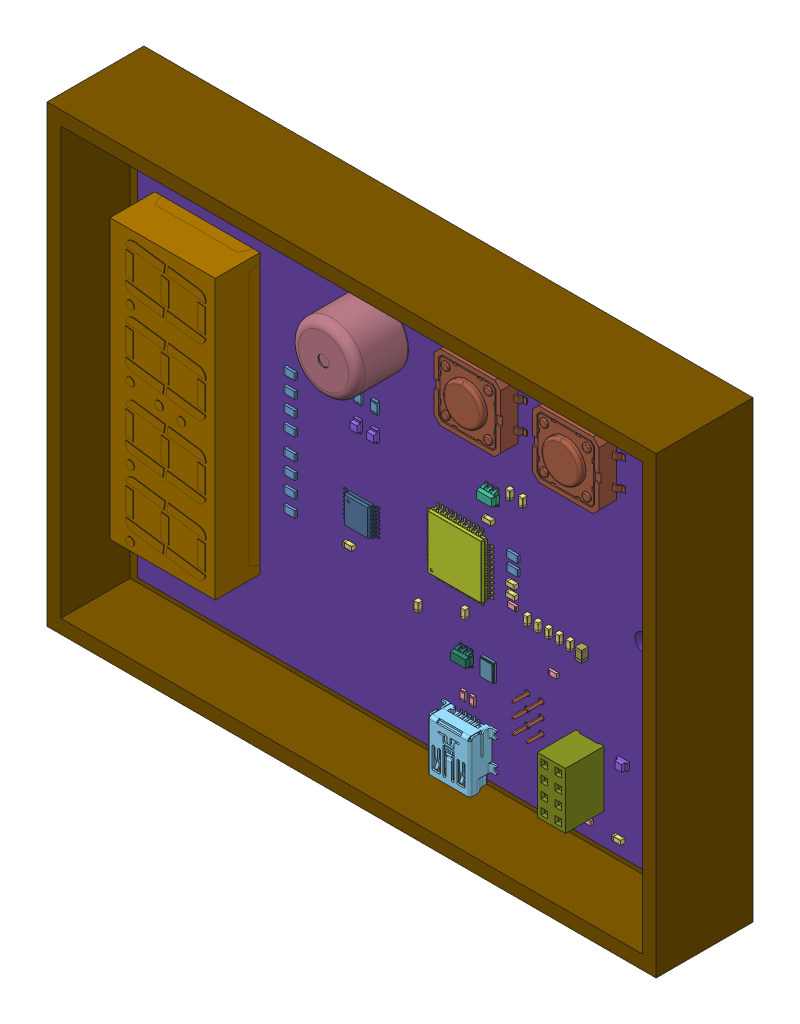
SolidWorks assembly Phase_B_Encloser_ASM_One, configuration Default. Lengths in mm.
Overall size (110 82 17.5).
96 component instances, 18 part files, 1 mates.
Components (placement in the parent):
- R_0805_2012Metric.STEP-1: R_0805_2012Metric.STEP [Default] at (136.75 -75.9525 1.63) x (0 1 0) z (0 0 1) size (2 1.2 0.45)
  - SOLID.STEP-1: SOLID.STEP [Default] at origin size (2 1.2 0.45)
- PinSocket_2x03_P2.54mm_Vertical.STEP-1: PinSocket_2x03_P2.54mm_Vertical.STEP [Default] at (166.9225 -107.335 1.13) x (-1 0 0) z (0 0 -1) size (5.08 7.62 10.1)
  - SOLID-0.STEP-1: SOLID-0.STEP [Default] at origin size (5.08 7.62 10.1)
- C_0603_1608Metric.STEP-1: C_0603_1608Metric.STEP [Default] at (175.1083 -95.3579 1.63) x (0 1 0) z (0 0 1) size (1.6 0.8 0.8)
  - SOLID-1.STEP-1: SOLID-1.STEP [Default] at origin size (1.6 0.8 0.8)
- C_0603_1608Metric.STEP-2: C_0603_1608Metric.STEP [Default] at (167.3681 -95.3139 1.63) x (0 1 0) z (0 0 1) size (1.6 0.8 0.8)
  - SOLID-1.STEP-1: SOLID-1.STEP [Default] at origin size (1.6 0.8 0.8)
- R_0603_1608Metric.STEP-1: R_0603_1608Metric.STEP [Default] at (178.1154 -121.5005 1.63) size (1.6 0.8 0.45)
  - SOLID-2.STEP-1: SOLID-2.STEP [Default] at origin size (1.6 0.8 0.45)
- R_0805_2012Metric.STEP-2: R_0805_2012Metric.STEP [Default] at (164.6638 -86.8628 1.63) size (2 1.2 0.45)
  - SOLID.STEP-1: SOLID.STEP [Default] at origin size (2 1.2 0.45)
- USB_Mini-B_Lumberg_2486_01_Horizontal.STEP-1: USB_Mini-B_Lumberg_2486_01_Horizontal.STEP [Default] at (156.7225 -119.07 1.63) size (9.9 9.21 5)
  - SOLID-3.STEP-1: SOLID-3.STEP [Default] at origin size (9.9 9.21 5)
- SOT-23-5.STEP-1: SOT-23-5.STEP [Default] at (160.6831 -79.2295 1.63) x (0 -1 0) z (0 0 1) size (2.8 2.9 1.55)
  - SOLID-4.STEP-1: SOLID-4.STEP [Default] at origin size (2.8 2.9 1.55)
- R_0805_2012Metric.STEP-3: R_0805_2012Metric.STEP [Default] at (124.46 -81.28 1.63) size (2 1.2 0.45)
  - SOLID.STEP-1: SOLID.STEP [Default] at origin size (2 1.2 0.45)
- TQFP-44_10x10mm_P0.8mm.STEP-1: TQFP-44_10x10mm_P0.8mm.STEP [Default] at (154.94 -91.44 1.63) x (0 1 0) z (0 0 1) size (12 12 1.1)
  - SOLID-5.STEP-1: SOLID-5.STEP [Default] at origin size (12 12 1.1)
- LED_0805_2012Metric.STEP-1: LED_0805_2012Metric.STEP [Default] at (136.66 -80.3425 1.63) x (0 1 0) z (0 0 1) size (2 1.25 1.1)
  - SOLID-6.STEP-1: SOLID-6.STEP [Default] at origin size (2 1.25 1.1)
- C_0603_1608Metric.STEP-3: C_0603_1608Metric.STEP [Default] at (164.6143 -92.9198 1.63) size (1.6 0.8 0.8)
  - SOLID-1.STEP-1: SOLID-1.STEP [Default] at origin size (1.6 0.8 0.8)
- CA56-12EWA.STEP-1: CA56-12EWA.STEP [Default] at (101.6 -81.28 1.63) size (19 50.3 12.2)
  - SOLID-7.STEP-1: SOLID-7.STEP [Default] at origin size (19 50.3 12.2)
- C_0603_1608Metric.STEP-4: C_0603_1608Metric.STEP [Default] at (160.3412 -83.2998 1.63) x (-1 0 0) z (0 0 1) size (1.6 0.8 0.8)
  - SOLID-1.STEP-1: SOLID-1.STEP [Default] at origin size (1.6 0.8 0.8)
- TSSOP-16_4.4x5mm_P0.65mm.STEP-1: TSSOP-16_4.4x5mm_P0.65mm.STEP [Default] at (137.16 -93.98 1.63) size (6.4 5 1.1)
  - SOLID-8.STEP-1: SOLID-8.STEP [Default] at origin size (6.4 5 1.1)
- PTS125_SMD_Button.STEP-1: PTS125_SMD_Button.STEP [Default] at (177.0425 -64.155 1.63) x (0 1 0) z (1 0 0) size (12 4.3 15.3)
  - SOLID-9.STEP-1: SOLID-9.STEP [Default] at origin size (12 4.3 15.3)
- C_0603_1608Metric.STEP-5: C_0603_1608Metric.STEP [Default] at (171.2411 -95.3579 1.63) x (0 1 0) z (0 0 1) size (1.6 0.8 0.8)
  - SOLID-1.STEP-1: SOLID-1.STEP [Default] at origin size (1.6 0.8 0.8)
- R_0603_1608Metric.STEP-2: R_0603_1608Metric.STEP [Default] at (171.895 -101.6 1.63) size (1.6 0.8 0.45)
  - SOLID-2.STEP-1: SOLID-2.STEP [Default] at origin size (1.6 0.8 0.45)
- C_0603_1608Metric.STEP-6: C_0603_1608Metric.STEP [Default] at (135.1928 -99.8408 1.63) x (-1 0 0) z (0 0 1) size (1.6 0.8 0.8)
  - SOLID-1.STEP-1: SOLID-1.STEP [Default] at origin size (1.6 0.8 0.8)
- C_0805_2012Metric.STEP-1: C_0805_2012Metric.STEP [Default] at (177.4051 -95.4592 1.63) x (0 1 0) z (0 0 1) size (2 1.25 1.25)
  - SOLID-10.STEP-1: SOLID-10.STEP [Default] at origin size (2 1.25 1.25)
- R_0805_2012Metric.STEP-4: R_0805_2012Metric.STEP [Default] at (124.46 -96.93 1.63) size (2 1.2 0.45)
  - SOLID.STEP-1: SOLID.STEP [Default] at origin size (2 1.2 0.45)
- R_0805_2012Metric.STEP-5: R_0805_2012Metric.STEP [Default] at (124.46 -99.88 1.63) size (2 1.2 0.45)
  - SOLID.STEP-1: SOLID.STEP [Default] at origin size (2 1.2 0.45)
- Buzzer_12x9.5RM7.6.STEP-1: Buzzer_12x9.5RM7.6.STEP [Default] at (139.7 -67.955 1.63) x (0 1 0) z (0 0 1) size (12 12 12.53)
  - SOLID-11.STEP-1: SOLID-11.STEP [Default] at origin size (12 12 12.53)
- R_0603_1608Metric.STEP-3: R_0603_1608Metric.STEP [Default] at (164.621 -94.7272 1.63) x (-1 0 0) z (0 0 1) size (1.6 0.8 0.45)
  - SOLID-2.STEP-1: SOLID-2.STEP [Default] at origin size (1.6 0.8 0.45)
- LED_0805_2012Metric.STEP-2: LED_0805_2012Metric.STEP [Default] at (139.7 -80.3425 1.63) x (0 1 0) z (0 0 1) size (2 1.25 1.1)
  - SOLID-6.STEP-1: SOLID-6.STEP [Default] at origin size (2 1.25 1.1)
- R_0603_1608Metric.STEP-4: R_0603_1608Metric.STEP [Default] at (157.3461 -113.1038 1.63) x (0 1 0) z (0 0 1) size (1.6 0.8 0.45)
  - SOLID-2.STEP-1: SOLID-2.STEP [Default] at origin size (1.6 0.8 0.45)
- R_0805_2012Metric.STEP-6: R_0805_2012Metric.STEP [Default] at (164.6674 -88.9903 1.63) size (2 1.2 0.45)
  - SOLID.STEP-1: SOLID.STEP [Default] at origin size (2 1.2 0.45)
- C_0603_1608Metric.STEP-7: C_0603_1608Metric.STEP [Default] at (173.1422 -95.3579 1.63) x (0 1 0) z (0 0 1) size (1.6 0.8 0.8)
  - SOLID-1.STEP-1: SOLID-1.STEP [Default] at origin size (1.6 0.8 0.8)
- C_0603_1608Metric.STEP-8: C_0603_1608Metric.STEP [Default] at (183.7777 -121.5005 1.63) size (1.6 0.8 0.8)
  - SOLID-1.STEP-1: SOLID-1.STEP [Default] at origin size (1.6 0.8 0.8)
- Crystal_SMD_Abracon_ABM8G-4Pin_3.2x2.5mm.STEP-1: Crystal_SMD_Abracon_ABM8G-4Pin_3.2x2.5mm.STEP [Default] at (160.167 -106.8176 1.63) x (0 1 0) z (0 0 1) size (3.2 2.5 0.64)
  - SOLID-12.STEP-1: SOLID-12.STEP [Default] at origin size (3.2 2.5 0.64)
- R_0805_2012Metric.STEP-7: R_0805_2012Metric.STEP [Default] at (124.46 -78.33 1.63) size (2 1.2 0.45)
  - SOLID.STEP-1: SOLID.STEP [Default] at origin size (2 1.2 0.45)
- R_0805_2012Metric.STEP-8: R_0805_2012Metric.STEP [Default] at (139.7 -75.9525 1.63) x (0 1 0) z (0 0 1) size (2 1.2 0.45)
  - SOLID.STEP-1: SOLID.STEP [Default] at origin size (2 1.2 0.45)
- R_0805_2012Metric.STEP-9: R_0805_2012Metric.STEP [Default] at (124.46 -93.98 1.63) size (2 1.2 0.45)
  - SOLID.STEP-1: SOLID.STEP [Default] at origin size (2 1.2 0.45)
- C_0603_1608Metric.STEP-9: C_0603_1608Metric.STEP [Default] at (164.6119 -91.194 1.63) x (-1 0 0) z (0 0 1) size (1.6 0.8 0.8)
  - SOLID-1.STEP-1: SOLID-1.STEP [Default] at origin size (1.6 0.8 0.8)
- C_0603_1608Metric.STEP-10: C_0603_1608Metric.STEP [Default] at (147.6552 -103.0061 1.63) x (0 -1 0) z (0 0 1) size (1.6 0.8 0.8)
  - SOLID-1.STEP-1: SOLID-1.STEP [Default] at origin size (1.6 0.8 0.8)
- C_0603_1608Metric.STEP-11: C_0603_1608Metric.STEP [Default] at (164.2172 -77.2255 1.63) x (0 -1 0) z (0 0 1) size (1.6 0.8 0.8)
  - SOLID-1.STEP-1: SOLID-1.STEP [Default] at origin size (1.6 0.8 0.8)
- C_0603_1608Metric.STEP-12: C_0603_1608Metric.STEP [Default] at (169.3071 -95.3345 1.63) x (0 1 0) z (0 0 1) size (1.6 0.8 0.8)
  - SOLID-1.STEP-1: SOLID-1.STEP [Default] at origin size (1.6 0.8 0.8)
- C_0603_1608Metric.STEP-13: C_0603_1608Metric.STEP [Default] at (156.1028 -99.9047 1.63) x (0 1 0) z (0 0 1) size (1.6 0.8 0.8)
  - SOLID-1.STEP-1: SOLID-1.STEP [Default] at origin size (1.6 0.8 0.8)
- SOT-23-6.STEP-1: SOT-23-6.STEP [Default] at (156.0168 -106.7769 1.63) x (0 1 0) z (0 0 1) size (2.8 2.9 1.55)
  - SOLID-13.STEP-1: SOLID-13.STEP [Default] at origin size (2.8 2.9 1.55)
- R_0805_2012Metric.STEP-10: R_0805_2012Metric.STEP [Default] at (124.46 -91.03 1.63) size (2 1.2 0.45)
  - SOLID.STEP-1: SOLID.STEP [Default] at origin size (2 1.2 0.45)
- R_0805_2012Metric.STEP-11: R_0805_2012Metric.STEP [Default] at (124.46 -84.23 1.63) size (2 1.2 0.45)
  - SOLID.STEP-1: SOLID.STEP [Default] at origin size (2 1.2 0.45)
- C_0603_1608Metric.STEP-14: C_0603_1608Metric.STEP [Default] at (166.5378 -77.2117 1.63) x (0 -1 0) z (0 0 1) size (1.6 0.8 0.8)
  - SOLID-1.STEP-1: SOLID-1.STEP [Default] at origin size (1.6 0.8 0.8)
- R_0805_2012Metric.STEP-12: R_0805_2012Metric.STEP [Default] at (124.46 -87.18 1.63) size (2 1.2 0.45)
  - SOLID.STEP-1: SOLID.STEP [Default] at origin size (2 1.2 0.45)
- PinSocket_2x04_P2.54mm_Vertical.STEP-1: PinSocket_2x04_P2.54mm_Vertical.STEP [Default] at (179.5825 -109.875 1.63) size (5.08 10.16 10.1)
  - SOLID-14.STEP-1: SOLID-14.STEP [Default] at origin size (5.08 10.16 10.1)
- LED_0805_2012Metric.STEP-3: LED_0805_2012Metric.STEP [Default] at (184.4796 -109.4399 1.63) size (2 1.25 1.1)
  - SOLID-6.STEP-1: SOLID-6.STEP [Default] at origin size (2 1.25 1.1)
- R_0603_1608Metric.STEP-5: R_0603_1608Metric.STEP [Default] at (155.706 -113.0772 1.63) x (0 1 0) z (0 0 1) size (1.6 0.8 0.45)
  - SOLID-2.STEP-1: SOLID-2.STEP [Default] at origin size (1.6 0.8 0.45)
- PTS125_SMD_Button.STEP-2: PTS125_SMD_Button.STEP [Default] at (159.2625 -64.155 1.63) x (0 1 0) z (1 0 0) size (12 4.3 15.3)
  - SOLID-9.STEP-1: SOLID-9.STEP [Default] at origin size (12 4.3 15.3)
- PCB.STEP-1: PCB.STEP [Default] at origin size (99.06 71.12 1.58)
- Encloser_Part_One-1: Encloser_Part_One [Default] at (145.2325 -89.175 -5.87) size (110 82 17.5)
Mates (geometry in assembly coordinates):
- Coincident7: coincident: point of PinSocket_2x03_P2.54mm_Vertical.STEP-1/SOLID-0.STEP-1; unknown of Encloser_Part_One-1
